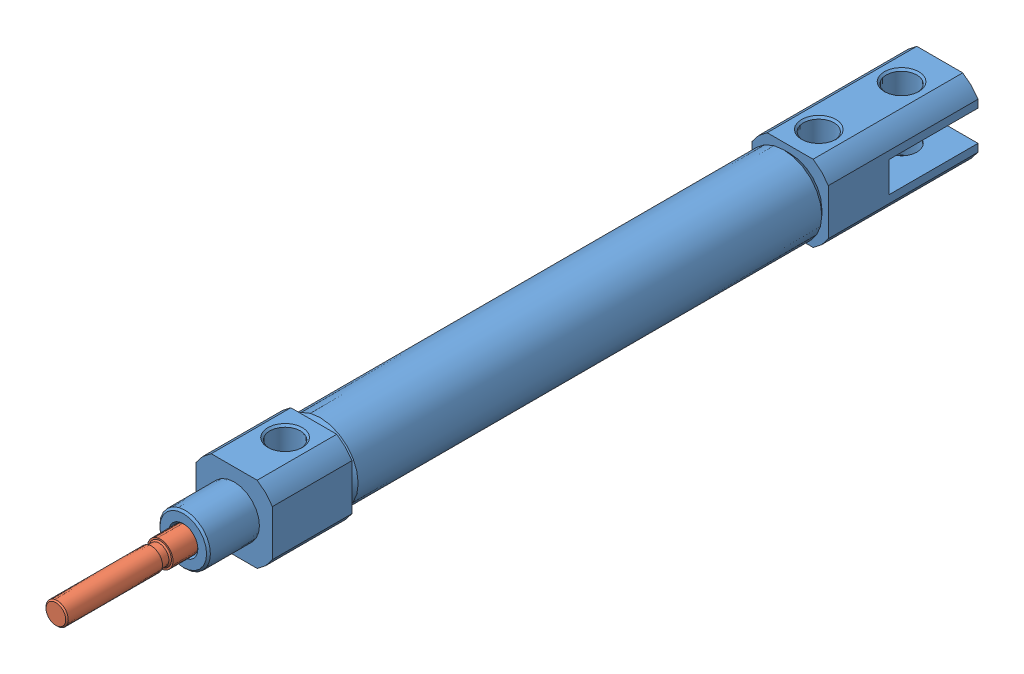
SolidWorks assembly Double Acting Cylinder, configuration Default. Lengths in mm.
Overall size (12 12 138.8).
2 component instances, 2 part files, 4 mates.
Components (placement in the parent):
- NCJ2-Body 10D^Double Acting Cylinder-1: NCJ2-Body 10D^Double Acting Cylinder [Default] at (43.4143 60.8033 93.9907) size (12 12 118.8) (virtual)
- NCJ2-Rod 10^Double Acting Cylinder-1: NCJ2-Rod 10^Double Acting Cylinder [Default] at (43.4143 60.8033 118.9907) x (0.997831 -0.065828 0) z (0 0 1) size (10 10 105.8) (virtual)
Mates (geometry in assembly coordinates):
- Concentric1: concentric anti-aligned: cylinder of Copy of NCJ2-Body 10D^Assem2-1 through (43.4143 60.8033 60.4339) axis (0 0 -1) radius 2; cylinder of NCJ2-Rod 10^Double Acting Cylinder-1 through (43.4143 60.8033 71.0907) axis (0 0 1) radius 5
- LimitDistance1: limit distance = 0 mm anti-aligned: plane of Copy of NCJ2-Rod 10^Assem2-1 through (43.4143 60.8033 66.0907) normal (0 0 -1); plane of NCJ2-Body 10D-1 through (43.4143 60.8033 66.0907) normal (0 0 1)
- Coincident1: coincident anti-aligned: plane of NCJ2-Body 10D^Assem2-1 through (43.4143 60.8033 66.0907) normal (0 0 1); plane of NCJ2-Rod 10^Assem2-1 through (43.4143 60.8033 66.0907) normal (0 0 -1)
- Coincident2: coincident anti-aligned: plane of NCJ2-Body 10D^Assem2-1 through (43.4143 60.8033 121.8907) normal (0 0 -1); plane of NCJ2-Rod 10^Assem2-1 through (43.4143 60.8033 121.8907) normal (0 0 1)
